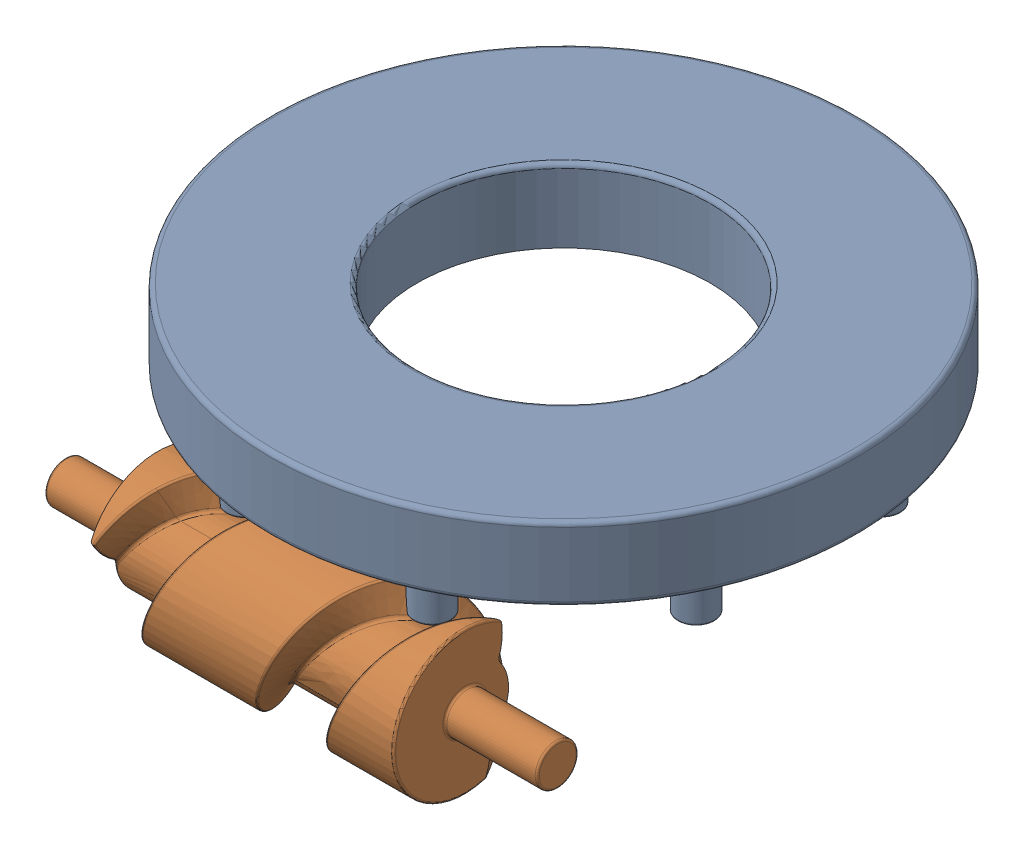
SolidWorks assembly Assembly Not Working Copy, configuration Default. Lengths in mm.
Overall size (4015.16 1818.88 4398.05).
2 component instances, 2 part files, 5 mates.
Components (placement in the parent):
- Rotating Table-1: Rotating Table [Default] at (0 350 0) x (0.999993 0 -0.003798) z (0.003798 0 0.999993) size (4000 850 4000)
- Driving Shaft-1: Driving Shaft [Default] at (0 -310.8256 1715.3852) x (1 0 0) z (0 -0.921471 -0.388447) size (3360 1020.93 1022.29)
Mates (geometry in assembly coordinates):
- Concentric1: concentric: circle of assembly; circle of Rotating Table-1; circle of assembly
- Coincident1: coincident: plane of assembly through (0 0 0) normal (0 1 0); plane of Rotating Table-1 through (-1647.173 0 -250.566) normal (0 -1 0); plane of assembly
- Coincident2: coincident aligned: line of Rotating Table-1 through (-467.5 0 350) axis (0 1 0)
- Concentric2: concentric: cylinder of assembly; cylinder of Driving Shaft-1 through (-1680.0377 -300 1720) axis (1 0 0) radius 140; circle of assembly
- Coincident3: coincident: plane of assembly through (0 0 0) normal (1 0 0); plane of Driving Shaft-1 through (0 -298.3003 1708.3552) normal (1 0 0); plane of assembly
